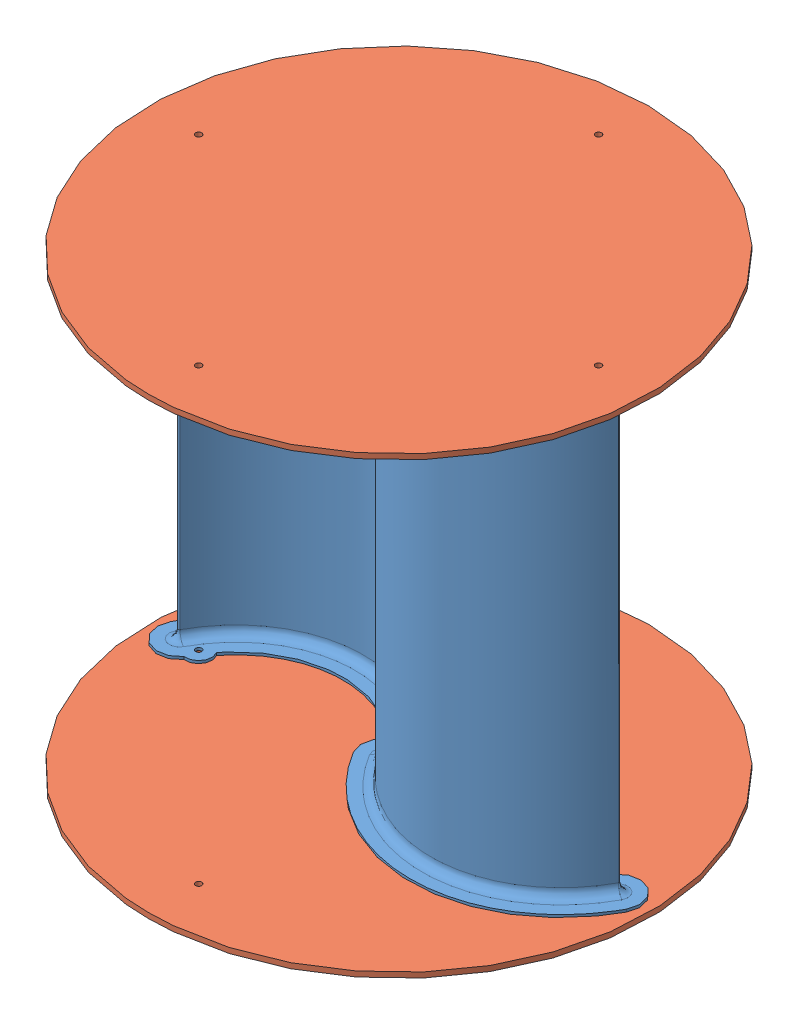
SolidWorks assembly Savonius_semi_eliptico_LL_v3, configuration Default. Lengths in mm.
Overall size (570 518 570).
4 component instances, 3 part files, 9 mates.
Components (placement in the parent):
- helice_Savonius_v3-1: helice_Savonius_v3 [Default] at origin size (550 503.02 550)
- tapa_circular_v3-1: tapa_circular_v3 [Default] at (0 503 0) size (570 6 570)
- tapa_helice_v3-1: tapa_helice_v3 [Default] at (0 500 0) size (550 13.02 212.77)
- tapa_circular_v3-2: tapa_circular_v3 [Default] at (0 -9 0) size (570 6 570)
Mates (geometry in assembly coordinates):
- Coincidente1: coincident anti-aligned: plane of tapa_circular_v3-1 through (0 503 0) normal (0 -1 0); plane of tapa_helice_v3-1 through (0 503 0) normal (0 1 0)
- Concéntrica1: concentric aligned: circle of tapa_circular_v3-1; circle of tapa_helice_v3-1
- Concéntrica2: concentric aligned: circle of tapa_circular_v3-1; circle of tapa_helice_v3-1
- Coincidente4: coincident anti-aligned: plane of helice_Savonius_v3-1 through (-119.0528 500 -79.0391) normal (0 1 0); plane of tapa_helice_v3-1 through (0 500 0) normal (0 -1 0)
- Concéntrica3: concentric aligned: circle of helice_Savonius_v3-1; circle of tapa_circular_v3-1
- Concéntrica4: concentric aligned: circle of helice_Savonius_v3-1; circle of tapa_circular_v3-1
- Concéntrica5: concentric aligned: circle of helice_Savonius_v3-1; circle of tapa_circular_v3-2
- Concéntrica6: concentric aligned: circle of helice_Savonius_v3-1; circle of tapa_circular_v3-2
- Coincidente9: coincident anti-aligned: plane of helice_Savonius_v3-1 through (0 -3 0) normal (0 -1 0); plane of tapa_circular_v3-2 through (0 -3 0) normal (0 1 0)
